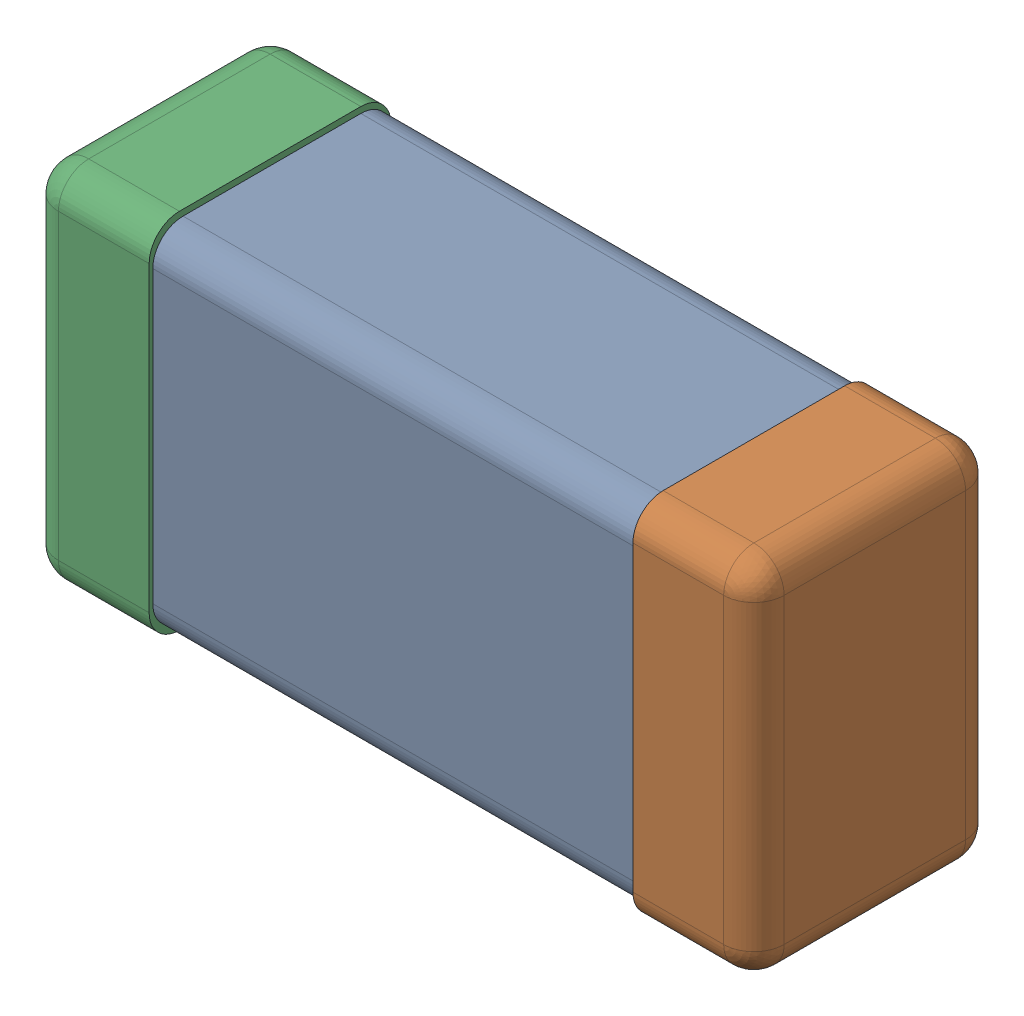
SolidWorks assembly C0201_020_21, configuration Standard. Lengths in mm.
Overall size (0.6 0.3 0.2).
3 component instances, 3 part files, 0 mates.
Components (placement in the parent):
- Part 3_2-1: Part 3_2 [Standard] at (0 0 -7.3015) size (0.5 0.29 0.2)
- Part 2_2-1: Part 2_2 [Standard] at (0 0 -7.3) size (0.1 0.3 0.2)
- Part 1_2-1: Part 1_2 [Standard] at (0 0 -7.3) size (0.1 0.3 0.2)
